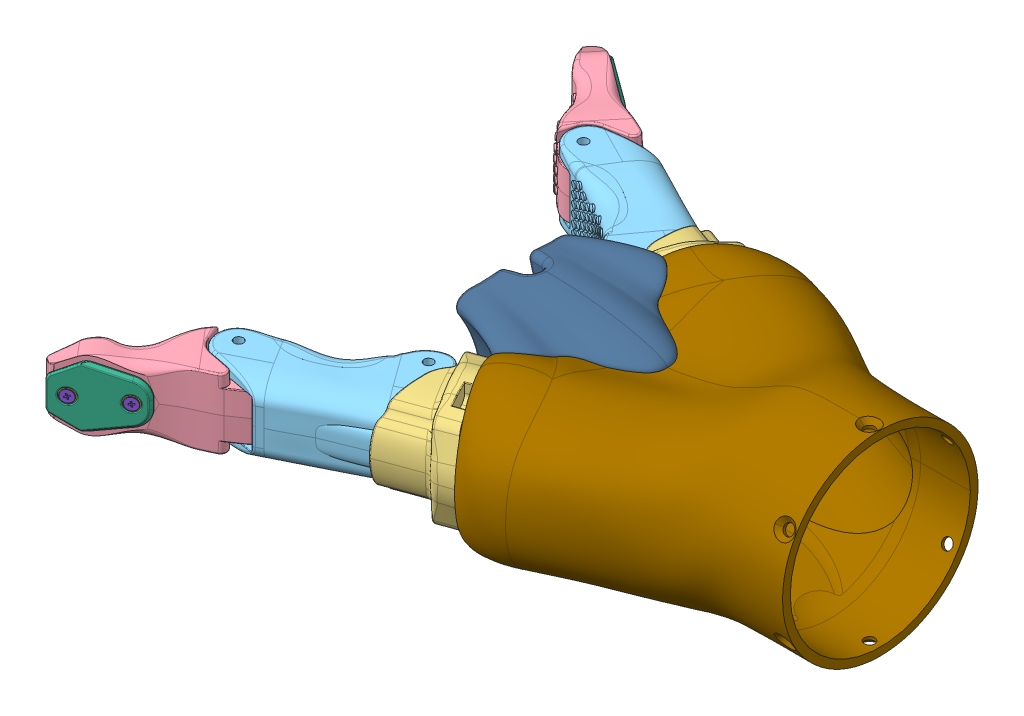
SolidWorks assembly KG-2, configuration Default. Lengths in mm.
Overall size (190.12 63.02 189.85).
35 component instances, 10 part files, 0 mates.
Components (placement in the parent):
- KG-2.STEP-1: KG-2.STEP [Default] at origin size (198.06 63.02 194.91)
  - AM 3540 0001 - Linear Actuator - 35mm - 40N - Dummy simple.STEP-1: AM 3540 0001 - Linear Actuator - 35mm - 40N - Dummy simple.STEP [Default] at (-86.7275 0 30.1692) x (-0.939693 0 0.34202) z (0 1 0) size (59.16 39 39) (hidden)
    - DummyActuator_D_faut.STEP-1: DummyActuator_D_faut.STEP [Default] at origin size (44.13 37 37)
    - MF3915 0001 - Mico finger actuator plastic cup for junction with hand_D_faut.STEP-1: MF3915 0001 - Mico finger actuator plastic cup for junction with hand_D_faut.STEP [Default] at (-13 0 0) x (-1 0 0) z (0 0 -1) size (15.02 39 39)
  - AM 3540 0001 - Linear Actuator - 35mm - 40N - Dummy simple.STEP-2: AM 3540 0001 - Linear Actuator - 35mm - 40N - Dummy simple.STEP [Default] at (-86.7275 0 -30.1692) x (-0.939693 0 -0.34202) z (0 -1 0) size (59.16 39 39) (hidden)
    - DummyActuator_D_faut.STEP-1: DummyActuator_D_faut.STEP [Default] at origin size (44.13 37 37)
    - MF3915 0001 - Mico finger actuator plastic cup for junction with hand_D_faut.STEP-1: MF3915 0001 - Mico finger actuator plastic cup for junction with hand_D_faut.STEP [Default] at (-13 0 0) x (-1 0 0) z (0 0 -1) size (15.02 39 39)
  - AM 3240 0004 - Plastic Finger Assembly Mico - 32mm - 2 Phalanges_simple_D_faut.STEP-1: AM 3240 0004 - Plastic Finger Assembly Mico - 32mm - 2 Phalanges_simple_D_faut.STEP [Default] at (-93.8204 0 -32.7508) x (-0.34202 0 0.939693) z (0.939693 0 0.34202) size (47.27 36.79 116.14)
    - MI 0000 0001 - 1.0.0.0011_simple_D_faut.STEP-1: MI 0000 0001 - 1.0.0.0011_simple_D_faut.STEP [Default] at (0 0 -13.5762) x (0 0 1) z (0 1 0) size (36.76 36.64 36.79)
    - MI 0000 0002 - 1.0.0.0005_simple_molded_version.STEP-1: MI 0000 0002 - 1.0.0.0005_simple_molded_version.STEP [Default] at (-0.0949 0 -66.3867) x (-0.34202 0 -0.939693) z (0 -1 0) size (53.08 21.63 24.15)
    - MI 0000 0004 - 1.0.0.0005_simple_D_faut.STEP-1: MI 0000 0004 - 1.0.0.0005_simple_D_faut.STEP [Default] at (5.2287 0 -24.6775) x (-0.173648 0 -0.984808) z (0 -1 0) size (57.72 28.12 23.54)
    - MI 1502 0001 - 1.0.0.0002_simple_D_faut.STEP-1: MI 1502 0001 - 1.0.0.0002_simple_D_faut.STEP [Default] at (-16.391 0 -80.0717) x (0 1 0) z (-0.97437 0 0.224951) size (19.37 25 1.26)
    - MH 0205 0003 - M2x5 washer, stainless, black oxyde, 0.3 thick_simple_D_faut.STEP-1: MH 0205 0003 - M2x5 washer, stainless, black oxyde, 0.3 thick_simple_D_faut.STEP [Default] at (-18.5389 0 -84.7073) x (-0.224951 0.000713 -0.97437) z (0.97437 0 -0.224951) size (5 5 0.3)
    - MH 0205 0003 - M2x5 washer, stainless, black oxyde, 0.3 thick_simple_D_faut.STEP-2: MH 0205 0003 - M2x5 washer, stainless, black oxyde, 0.3 thick_simple_D_faut.STEP [Default] at (-21.9132 0 -99.3229) x (-0.224951 0.000713 -0.97437) z (0.97437 0 -0.224951) size (5 5 0.3)
    - MH 0204 0004 - Lamix M2x4 stainless steel screw, head 0.3 thick,  black colored_simple_D_faut.STEP-1: MH 0204 0004 - Lamix M2x4 stainless steel screw, head 0.3 thick,  black colored_simple_D_faut.STEP [Default] at (-14.6414 0 -85.6071) x (-0.028802 0.991769 -0.124755) z (0.2231 0.128036 0.96635) size (4 4.3 4)
    - MH 0204 0004 - Lamix M2x4 stainless steel screw, head 0.3 thick,  black colored_simple_D_faut.STEP-2: MH 0204 0004 - Lamix M2x4 stainless steel screw, head 0.3 thick,  black colored_simple_D_faut.STEP [Default] at (-18.0157 0 -100.2227) x (0.215322 0.289446 0.932661) z (0.065111 -0.957194 0.282028) size (4 4.3 4)
    - MH 0204 0004 - Lamix M2x4 stainless steel screw, head 0.3 thick,  black colored_simple_D_faut.STEP-3: MH 0204 0004 - Lamix M2x4 stainless steel screw, head 0.3 thick,  black colored_simple_D_faut.STEP [Default] at (-0.0949 -7.35 -66.3867) x (-0.96685 0 -0.255343) z (-0.255343 0 0.96685) size (4 4.3 4) (hidden)
    - MH 0204 0004 - Lamix M2x4 stainless steel screw, head 0.3 thick,  black colored_simple_D_faut.STEP-4: MH 0204 0004 - Lamix M2x4 stainless steel screw, head 0.3 thick,  black colored_simple_D_faut.STEP [Default] at (10.5 -7.35 -23.5762) x (-0.96685 0 -0.255343) z (-0.255343 0 0.96685) size (4 4.3 4) (hidden)
    - MH 0204 0004 - Lamix M2x4 stainless steel screw, head 0.3 thick,  black colored_simple_D_faut.STEP-5: MH 0204 0004 - Lamix M2x4 stainless steel screw, head 0.3 thick,  black colored_simple_D_faut.STEP [Default] at (-0.0949 7.35 -66.3867) size (4 4.3 4) (hidden)
    - MH 0204 0004 - Lamix M2x4 stainless steel screw, head 0.3 thick,  black colored_simple_D_faut.STEP-6: MH 0204 0004 - Lamix M2x4 stainless steel screw, head 0.3 thick,  black colored_simple_D_faut.STEP [Default] at (10.5 7.35 -23.5762) size (4 4.3 4) (hidden)
  - AM 3240 0004 - Plastic Finger Assembly Mico - 32mm - 2 Phalanges_simple_D_faut.STEP-2: AM 3240 0004 - Plastic Finger Assembly Mico - 32mm - 2 Phalanges_simple_D_faut.STEP [Default] at (-93.8204 0 32.7508) x (-0.34202 0 -0.939693) z (0.939693 0 -0.34202) size (47.27 36.79 116.14)
    - MI 0000 0001 - 1.0.0.0011_simple_D_faut.STEP-1: MI 0000 0001 - 1.0.0.0011_simple_D_faut.STEP [Default] at (0 0 -13.5762) x (0 0 1) z (0 1 0) size (36.76 36.64 36.79)
    - MI 0000 0002 - 1.0.0.0005_simple_molded_version.STEP-1: MI 0000 0002 - 1.0.0.0005_simple_molded_version.STEP [Default] at (-0.0949 0 -66.3867) x (-0.34202 0 -0.939693) z (0 -1 0) size (53.08 21.63 24.15)
    - MI 0000 0004 - 1.0.0.0005_simple_D_faut.STEP-1: MI 0000 0004 - 1.0.0.0005_simple_D_faut.STEP [Default] at (5.2287 0 -24.6775) x (-0.173648 0 -0.984808) z (0 -1 0) size (57.72 28.12 23.54)
    - MI 1502 0001 - 1.0.0.0002_simple_D_faut.STEP-1: MI 1502 0001 - 1.0.0.0002_simple_D_faut.STEP [Default] at (-16.391 0 -80.0717) x (0 1 0) z (-0.97437 0 0.224951) size (19.37 25 1.26)
    - MH 0205 0003 - M2x5 washer, stainless, black oxyde, 0.3 thick_simple_D_faut.STEP-1: MH 0205 0003 - M2x5 washer, stainless, black oxyde, 0.3 thick_simple_D_faut.STEP [Default] at (-18.5389 0 -84.7073) x (-0.224951 0.000713 -0.97437) z (0.97437 0 -0.224951) size (5 5 0.3)
    - MH 0205 0003 - M2x5 washer, stainless, black oxyde, 0.3 thick_simple_D_faut.STEP-2: MH 0205 0003 - M2x5 washer, stainless, black oxyde, 0.3 thick_simple_D_faut.STEP [Default] at (-21.9132 0 -99.3229) x (-0.224951 0.000713 -0.97437) z (0.97437 0 -0.224951) size (5 5 0.3)
    - MH 0204 0004 - Lamix M2x4 stainless steel screw, head 0.3 thick,  black colored_simple_D_faut.STEP-1: MH 0204 0004 - Lamix M2x4 stainless steel screw, head 0.3 thick,  black colored_simple_D_faut.STEP [Default] at (-14.6414 0 -85.6071) x (-0.028802 0.991769 -0.124755) z (0.2231 0.128036 0.96635) size (4 4.3 4)
    - MH 0204 0004 - Lamix M2x4 stainless steel screw, head 0.3 thick,  black colored_simple_D_faut.STEP-2: MH 0204 0004 - Lamix M2x4 stainless steel screw, head 0.3 thick,  black colored_simple_D_faut.STEP [Default] at (-18.0157 0 -100.2227) x (0.215322 0.289446 0.932661) z (0.065111 -0.957194 0.282028) size (4 4.3 4)
    - MH 0204 0004 - Lamix M2x4 stainless steel screw, head 0.3 thick,  black colored_simple_D_faut.STEP-3: MH 0204 0004 - Lamix M2x4 stainless steel screw, head 0.3 thick,  black colored_simple_D_faut.STEP [Default] at (-0.0949 -7.35 -66.3867) x (-0.96685 0 -0.255343) z (-0.255343 0 0.96685) size (4 4.3 4) (hidden)
    - MH 0204 0004 - Lamix M2x4 stainless steel screw, head 0.3 thick,  black colored_simple_D_faut.STEP-4: MH 0204 0004 - Lamix M2x4 stainless steel screw, head 0.3 thick,  black colored_simple_D_faut.STEP [Default] at (10.5 -7.35 -23.5762) x (-0.96685 0 -0.255343) z (-0.255343 0 0.96685) size (4 4.3 4) (hidden)
    - MH 0204 0004 - Lamix M2x4 stainless steel screw, head 0.3 thick,  black colored_simple_D_faut.STEP-5: MH 0204 0004 - Lamix M2x4 stainless steel screw, head 0.3 thick,  black colored_simple_D_faut.STEP [Default] at (-0.0949 7.35 -66.3867) size (4 4.3 4) (hidden)
    - MH 0204 0004 - Lamix M2x4 stainless steel screw, head 0.3 thick,  black colored_simple_D_faut.STEP-6: MH 0204 0004 - Lamix M2x4 stainless steel screw, head 0.3 thick,  black colored_simple_D_faut.STEP [Default] at (10.5 7.35 -23.5762) size (4 4.3 4) (hidden)
  - MT0062 0002 - Hand Shell Mico_D_faut.STEP-1: MT0062 0002 - Hand Shell Mico_D_faut.STEP [Default] at origin size (108.05 63.02 113.68)
  - MO 0000 0009 - rubber part handfront_D_faut.STEP-1: MO 0000 0009 - rubber part handfront_D_faut.STEP [Default] at (-21.4262 -5.1521 0) size (50.65 54.11 65.34)
